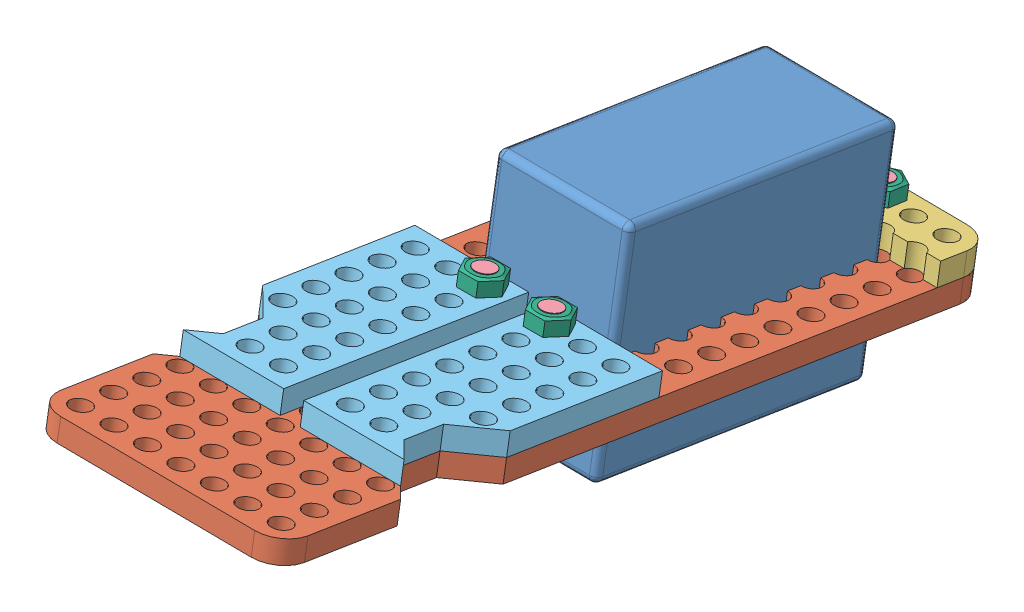
SolidWorks assembly 4, configuration Default. Lengths in mm.
Overall size (37.11 42.47 106.77).
13 component instances, 6 part files, 35 mates.
Components (placement in the parent):
- 4-3-1-1: 4-3-1 [Default] at (40.9889 91.1903 95.7798) x (0.000542 -0.156226 -0.987721) z (0.999972 -0.007345 0.001711) size (40.8 36.4 20)
- 4-0-1-1: 4-0-1 [Default] at (41.1019 111.804 118.2352) x (0.000542 -0.156226 -0.987721) z (0.999972 -0.007345 0.001711) size (107 3.25 37)
- 4-1-1-1: 4-1-1 [Default] at (41.1532 107.2808 68.8353) x (0.999972 -0.007345 0.001711) z (-0.000542 0.156226 0.987721) size (37 3.25 8)
- 9-3-1-8: 9-3-1 [Default] at (46.1966 112.8452 67.4517) x (-0.000542 0.156226 0.987721) z (0.999972 -0.007345 0.001711) size (5 10.48 5)
- 9-3-1-9: 9-3-1 [Default] at (36.1969 112.9187 67.4346) x (-0.000542 0.156226 0.987721) z (0.999972 -0.007345 0.001711) size (5 10.48 5)
- 4-2-1-1: 4-2-1 [Default] at (51.118 117.284 132.5604) x (-0.000542 0.156226 0.987721) z (-0.999972 0.007345 -0.001711) size (37 3.25 17)
- 4-2-1-2: 4-2-1 [Default] at (31.143 120.6409 132.0185) x (-0.000542 0.156226 0.987721) z (0.999972 -0.007345 0.001711) size (37 3.25 17)
- 9-3-1-14: 9-3-1 [Default] at (46.1695 120.6566 116.8378) x (0.000542 -0.156226 -0.987721) z (-0.999972 0.007345 -0.001711) size (5 10.48 5)
- 9-3-1-15: 9-3-1 [Default] at (36.1698 120.73 116.8207) x (-0.000542 0.156226 0.987721) z (0.999972 -0.007345 0.001711) size (5 10.48 5)
- 10-1-1-1: 10-1-1 [Default] at (36.1796 110.647 67.7939) x (-0.999972 0.007345 -0.001711) z (0.000542 -0.156226 -0.987721) size (5.11 5.14 5.85)
- 10-1-1-2: 10-1-1 [Default] at (36.1525 118.4583 117.18) x (-0.000542 0.156226 0.987721) z (-0.999972 0.007345 -0.001711) size (5.11 5.14 5.85)
- 10-1-1-3: 10-1-1 [Default] at (46.1522 118.3849 117.1971) x (-0.000542 0.156226 0.987721) z (-0.999972 0.007345 -0.001711) size (5.11 5.14 5.85)
- 10-1-1-5: 10-1-1 [Default] at (46.1793 110.5735 67.811) x (-0.999972 0.007345 -0.001711) z (0.000542 -0.156226 -0.987721) size (5.11 5.14 5.85)
Mates (geometry in assembly coordinates):
- Coincident33: coincident anti-aligned: plane of 4-0-1-1 through (41.1264 115.014 117.7275) normal (0.007522 0.987694 -0.156218); plane of 4-1-1-1 through (55.6528 107.1743 68.8601) normal (-0.007522 -0.987694 0.156218)
- Concentric42: concentric anti-aligned: cylinder of 4-0-1-1 through (46.1533 107.166 68.35) axis (-0.007522 -0.987694 0.156218) radius 1.5025; cylinder of 9-3-1-8 through (46.1289 103.956 68.8577) axis (0.007522 0.987694 -0.156218) radius 1.5
- Coincident36: coincident anti-aligned: plane of 4-0-1-1 through (41.1019 111.804 118.2352) normal (-0.007522 -0.987694 0.156218); plane of 9-3-1-8 through (46.1289 103.956 68.8577) normal (0.007522 0.987694 -0.156218)
- Concentric45: concentric anti-aligned: cylinder of 4-0-1-1 through (36.1536 107.2395 68.3329) axis (-0.007522 -0.987694 0.156218) radius 1.5025; cylinder of 9-3-1-9 through (36.1292 104.0294 68.8406) axis (0.007522 0.987694 -0.156218) radius 1.5
- Coincident37: coincident anti-aligned: plane of 4-0-1-1 through (41.1019 111.804 118.2352) normal (-0.007522 -0.987694 0.156218); plane of 9-3-1-9 through (36.1292 104.0294 68.8406) normal (0.007522 0.987694 -0.156218)
- Coincident38: coincident aligned: plane of 4-0-1-1 through (22.6269 115.1499 117.6958) normal (-0.999972 0.007345 -0.001711); plane of 4-1-1-1 through (22.6782 110.6267 68.2959) normal (-0.999972 0.007345 -0.001711)
- Parallel17: parallel anti-aligned: plane of 4-0-1-1; plane of 9-3-1-8
- Parallel18: parallel anti-aligned: plane of 4-0-1-1; plane of 9-3-1-9
- Coincident60: coincident anti-aligned: plane of 4-0-1-1 through (41.1264 115.014 117.7275) normal (0.007522 0.987694 -0.156218); plane of 4-2-1-1 through (51.118 117.284 132.5604) normal (-0.007522 -0.987694 0.156218)
- Coincident61: coincident aligned: plane of 4-0-1-1 through (59.6259 114.8782 117.7591) normal (0.999972 -0.007345 0.001711); plane of 4-2-1-1 through (59.6522 117.5414 113.7944) normal (0.999972 -0.007345 0.001711)
- Concentric61: concentric aligned: cylinder of 4-0-1-1 through (56.1151 118.0284 137.5076) axis (-0.007522 -0.987694 0.156218) radius 1.5025; cylinder of 4-2-1-1 through (56.1396 121.2384 136.9999) axis (-0.007522 -0.987694 0.156218) radius 1.5025
- Coincident62: coincident anti-aligned: plane of 4-0-1-1 through (41.1264 115.014 117.7275) normal (0.007522 0.987694 -0.156218); plane of 4-2-1-2 through (31.1185 117.4309 132.5262) normal (-0.007522 -0.987694 0.156218)
- Coincident64: coincident aligned: plane of 4-0-1-1 through (22.6269 115.1499 117.6958) normal (-0.999972 0.007345 -0.001711); plane of 4-2-1-2 through (22.6288 114.6031 114.2388) normal (-0.999972 0.007345 -0.001711)
- Concentric62: concentric anti-aligned: cylinder of 4-0-1-1 through (31.1267 115.0875 117.7104) axis (-0.007522 -0.987694 0.156218) radius 1.5025; cylinder of 4-2-1-2 through (31.1267 115.0875 117.7104) axis (0.007522 0.987694 -0.156218) radius 1.5025
- Concentric63: concentric anti-aligned: cylinder of 4-0-1-1 through (36.1265 115.0508 117.7189) axis (-0.007522 -0.987694 0.156218) radius 1.5025; cylinder of 9-3-1-15 through (36.1021 111.8408 118.2266) axis (0.007522 0.987694 -0.156218) radius 1.5
- Coincident65: coincident anti-aligned: plane of 4-0-1-1 through (41.1019 111.804 118.2352) normal (-0.007522 -0.987694 0.156218); plane of 9-3-1-15 through (36.1021 111.8408 118.2266) normal (0.007522 0.987694 -0.156218)
- Concentric64: concentric aligned: cylinder of 4-0-1-1 through (41.1535 107.2027 68.3414) axis (-0.007522 -0.987694 0.156218) radius 1.5025; cylinder of 4-1-1-1 through (41.1779 110.4127 67.8337) axis (-0.007522 -0.987694 0.156218) radius 1.5025
- Concentric65: concentric anti-aligned: cylinder of 4-0-1-1 through (46.1262 114.9773 117.736) axis (-0.007522 -0.987694 0.156218) radius 1.5025; cylinder of 9-3-1-14 through (46.1018 111.7673 118.2437) axis (0.007522 0.987694 -0.156218) radius 1.5
- Coincident66: coincident anti-aligned: plane of 4-0-1-1 through (41.1019 111.804 118.2352) normal (-0.007522 -0.987694 0.156218); plane of 9-3-1-14 through (46.1018 111.7673 118.2437) normal (0.007522 0.987694 -0.156218)
- Coincident67: coincident aligned: plane of 4-0-1-1; plane of 9-3-1-14
- Coincident68: coincident anti-aligned: plane of 4-0-1-1; plane of 9-3-1-15
- Concentric70: concentric aligned: cylinder of 9-3-1-9 through (36.1292 104.0294 68.8406) axis (0.007522 0.987694 -0.156218) radius 1.5; cylinder of 10-1-1-1 through (36.1678 109.0967 68.0391) axis (0.007522 0.987694 -0.156218) radius 1.5025
- Coincident77: coincident anti-aligned: plane of 4-1-1-1 through (55.6773 110.3843 68.3524) normal (0.007522 0.987694 -0.156218); plane of 10-1-1-1 through (36.1781 110.4495 67.8252) normal (-0.007522 -0.987694 0.156218)
- Parallel24: parallel anti-aligned: plane of 4-1-1-1; plane of 10-1-1-1
- Concentric71: concentric aligned: cylinder of 9-3-1-8 through (46.1289 103.956 68.8577) axis (0.007522 0.987694 -0.156218) radius 1.5; cylinder of 10-1-1-5 through (46.1675 109.0233 68.0562) axis (0.007522 0.987694 -0.156218) radius 1.5025
- Coincident79: coincident anti-aligned: plane of 4-1-1-1 through (55.6773 110.3843 68.3524) normal (0.007522 0.987694 -0.156218); plane of 10-1-1-5 through (46.1778 110.376 67.8423) normal (-0.007522 -0.987694 0.156218)
- Parallel25: parallel anti-aligned: plane of 4-1-1-1; plane of 10-1-1-5
- Concentric74: concentric aligned: cylinder of 9-3-1-14 through (46.1018 111.7673 118.2437) axis (0.007522 0.987694 -0.156218) radius 1.5; cylinder of 10-1-1-3 through (46.1404 116.8346 117.4423) axis (0.007522 0.987694 -0.156218) radius 1.5025
- Coincident85: coincident anti-aligned: plane of 4-2-1-1 through (51.1424 120.494 132.0527) normal (0.007522 0.987694 -0.156218); plane of 10-1-1-3 through (46.1507 118.1873 117.2283) normal (-0.007522 -0.987694 0.156218)
- Parallel28: parallel aligned: plane of 10-1-1-3; plane of 4-2-1-1
- Concentric75: concentric aligned: cylinder of 9-3-1-15 through (36.1021 111.8408 118.2266) axis (0.007522 0.987694 -0.156218) radius 1.5; cylinder of 10-1-1-2 through (36.1407 116.908 117.4252) axis (0.007522 0.987694 -0.156218) radius 1.5025
- Coincident87: coincident anti-aligned: plane of 4-2-1-2 through (31.143 120.6409 132.0185) normal (0.007522 0.987694 -0.156218); plane of 10-1-1-2 through (36.151 118.2608 117.2112) normal (-0.007522 -0.987694 0.156218)
- Parallel29: parallel aligned: plane of 4-2-1-2; plane of 10-1-1-2
- Coincident90: coincident anti-aligned: plane of 4-0-1-1 through (31.1267 115.0875 117.7104) normal (0.999972 -0.007345 0.001711); plane of 4-3-1-1 through (31.252 130.4028 110.2259) normal (-0.999972 0.007345 -0.001711)
- Coincident91: coincident anti-aligned: plane of 4-3-1-1 through (31.252 130.4028 110.2259) normal (-0.000542 0.156226 0.987721); plane of 4-0-1-1 through (41.1291 114.2329 112.7889) normal (0.000542 -0.156226 -0.987721)
